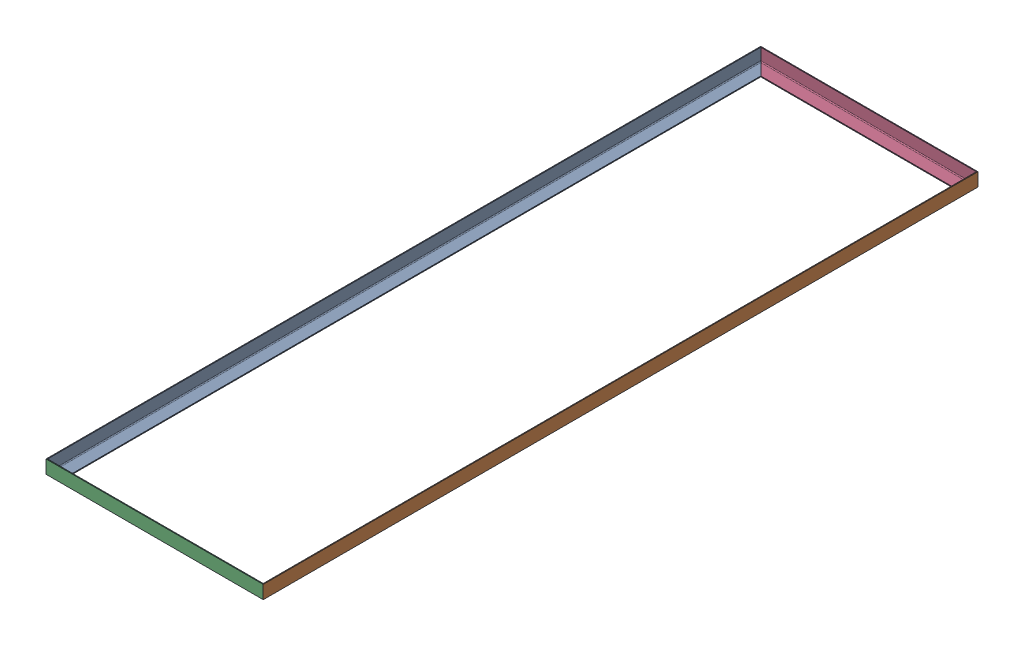
SolidWorks assembly Jig Table_001, configuration Default. Lengths in mm.
Overall size (831.85 50.8 2736.85).
4 component instances, 2 part files, 9 mates.
Components (placement in the parent):
- 2inx0.125in_angle iron_107.75in-1: 2inx0.125in_angle iron_107.75in [8968K586] at origin size (50.8 50.8 2736.85)
- 2inx0.125in_angle iron_107.75in-2: 2inx0.125in_angle iron_107.75in [8968K586] at (781.05 0 0) x (-1 0 0) z (0 0 -1) size (50.8 50.8 2736.85)
- 2inx0.125in_angle iron_32.75in-3: 2inx0.125in_angle iron_32.75in [8968K586] at (390.525 0 1343.025) x (0 0 -1) z (1 0 0) size (50.8 50.8 831.85)
- 2inx0.125in_angle iron_32.75in-4: 2inx0.125in_angle iron_32.75in [8968K586] at (390.525 0 -1343.025) x (0 0 1) z (-1 0 0) size (50.8 50.8 831.85)
Mates (geometry in assembly coordinates):
- Coincident1: coincident aligned: plane of 8968K586_Zinc-Galvanized Low-Carbon Steel 90 Degree Angle_6-1 through (-25.4 -25.4 -1368.425) normal (0 -1 0); plane of 8968K586_Zinc-Galvanized Low-Carbon Steel 90 Degree Angle_6-2 through (806.45 -25.4 1368.425) normal (0 -1 0)
- Coincident2: coincident aligned: plane of 8968K586_Zinc-Galvanized Low-Carbon Steel 90 Degree Angle_6-1 through (-25.4 -25.4 -1368.425) normal (0 -1 0); plane of 8968K586_Zinc-Galvanized Low-Carbon Steel 90 Degree Angle_3-3 through (-25.4 -25.4 1368.425) normal (0 -1 0)
- Coincident3: coincident aligned: plane of 8968K586_Zinc-Galvanized Low-Carbon Steel 90 Degree Angle_6-2 through (806.45 -25.4 1368.425) normal (0 -1 0); plane of 8968K586_Zinc-Galvanized Low-Carbon Steel 90 Degree Angle_3-4 through (806.45 -25.4 -1368.425) normal (0 -1 0)
- Coincident10: coincident anti-aligned: plane of 8968K586_Zinc-Galvanized Low-Carbon Steel 90 Degree Angle_6-1 through (-25.4 -25.4 1368.425) normal (0.707107 0 0.707107); plane of 8968K586_Zinc-Galvanized Low-Carbon Steel 90 Degree Angle_3-3 through (-25.4 -25.4 1368.425) normal (-0.707107 0 -0.707107)
- Coincident11: coincident aligned: line of 8968K586_Zinc-Galvanized Low-Carbon Steel 90 Degree Angle_6-1 through (-25.4 25.4 1368.425) axis (0 -1 0); line of 8968K586_Zinc-Galvanized Low-Carbon Steel 90 Degree Angle_3-3 through (-25.4 25.4 1368.425) axis (0 -1 0)
- Coincident12: coincident anti-aligned: plane of 8968K586_Zinc-Galvanized Low-Carbon Steel 90 Degree Angle_6-2 through (806.45 -25.4 -1368.425) normal (-0.707107 0 -0.707107); plane of 8968K586_Zinc-Galvanized Low-Carbon Steel 90 Degree Angle_3-4 through (806.45 -25.4 -1368.425) normal (0.707107 0 0.707107)
- Coincident13: coincident aligned: line of 8968K586_Zinc-Galvanized Low-Carbon Steel 90 Degree Angle_6-2 through (806.45 25.4 -1368.425) axis (0 -1 0); line of 8968K586_Zinc-Galvanized Low-Carbon Steel 90 Degree Angle_3-4 through (806.45 25.4 -1368.425) axis (0 -1 0)
- Coincident15: coincident aligned: line of 8968K586_Zinc-Galvanized Low-Carbon Steel 90 Degree Angle_6-1 through (-25.4 25.4 -1368.425) axis (0 -1 0); line of 8968K586_Zinc-Galvanized Low-Carbon Steel 90 Degree Angle_3-4 through (-25.4 25.4 -1368.425) axis (0 -1 0)
- Coincident16: coincident aligned: line of 8968K586_Zinc-Galvanized Low-Carbon Steel 90 Degree Angle_6-2 through (806.45 25.4 1368.425) axis (0 -1 0); line of 8968K586_Zinc-Galvanized Low-Carbon Steel 90 Degree Angle_3-3 through (806.45 25.4 1368.425) axis (0 -1 0)
